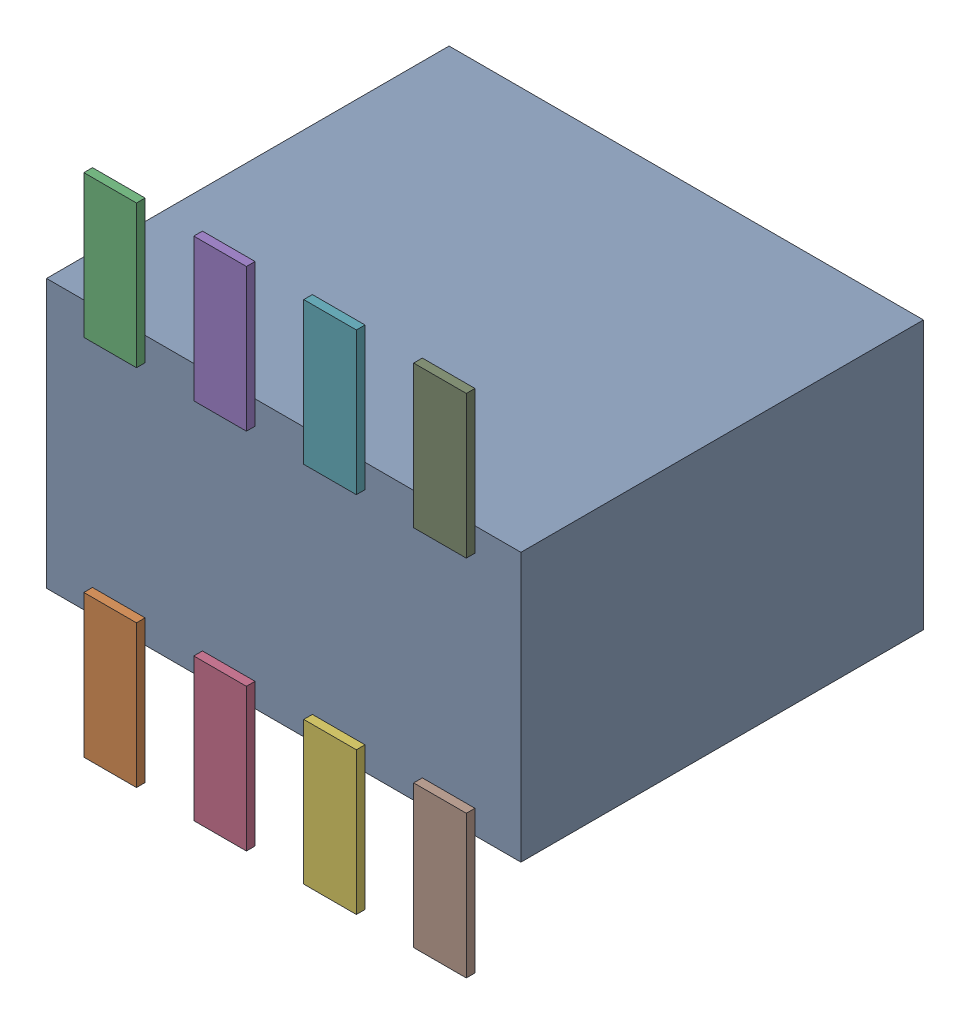
SolidWorks assembly J2_1.step, configuration Default. Lengths in mm.
Overall size (5.48 5.85 4.75).
3 component instances, 2 part files, 0 mates.
Components (placement in the parent):
- 9705581488.step-1: 9705581488.step [Default] at (208.451 98.62 -1.0914) x (1 0 0) z (0 0 -1) size (5.48 5.85 4.75)
  - Body_6.step-5: Body_6.step [Default] at (0 0 0.1) size (5.48 3.1 4.65)
  - Pins_3.step-5: Pins_3.step [Default] at origin size (4.42 5.85 0.1)
